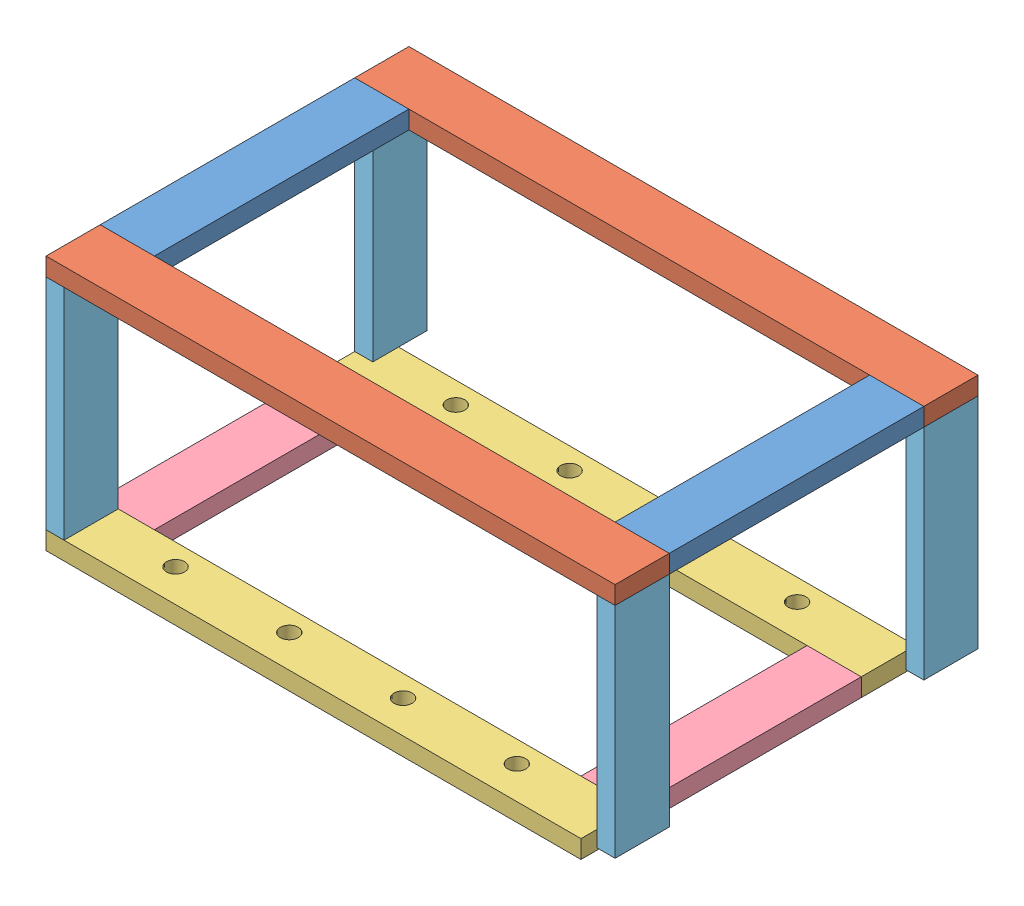
SolidWorks assembly 2.10 stand assembly, configuration Default. Lengths in mm.
Overall size (400.2 179.4 255.2).
12 component instances, 5 part files, 30 mates.
Components (placement in the parent):
- 2.10 steel stock - upper short horizontal-1: 2.10 steel stock - upper short horizontal [Default] at (-143.9565 137.1754 -48.2285) size (38.1 12.7 179)
- 2.10 steel stock - upper short horizontal-2: 2.10 steel stock - upper short horizontal [Default] at (218.1435 137.1754 -48.2285) size (38.1 12.7 179)
- 2.10 steel stock - upper long horizontal-1: 2.10 steel stock - upper long horizontal [Default] at (-143.9565 137.1754 -48.2285) size (400.2 12.7 38.1)
- 2.10 steel stock - upper long horizontal-2: 2.10 steel stock - upper long horizontal [Default] at (-143.9565 137.1754 168.8715) size (400.2 12.7 38.1)
- 2.10 steel stock - middle long horizontal-1: 2.10 steel stock - middle long horizontal [Default] at (-143.9565 -29.5246 168.8715) size (376.2 12.7 38.1)
- 2.10 steel stock - middle long horizontal-2: 2.10 steel stock - middle long horizontal [Default] at (-143.9565 -29.5246 -28.2285) size (376.2 12.7 38.1)
- 2.10 steel stock - middle short horizontal-1: 2.10 steel stock - middle short horizontal [Default] at (-143.9565 -29.5246 -28.2285) size (38.1 12.7 159)
- 2.10 steel stock - middle short horizontal-2: 2.10 steel stock - middle short horizontal [Default] at (194.1435 -29.5246 -28.2285) size (38.1 12.7 159)
- 2.10 steel stock - upper leg-1: 2.10 steel stock - upper leg [Default] at (-131.2565 -16.8246 168.8715) x (0 0 -1) z (1 0 0) size (38.1 154 12.7)
- 2.10 steel stock - upper leg-2: 2.10 steel stock - upper leg [Default] at (-131.2565 -16.8246 -48.2285) x (0 0 -1) z (1 0 0) size (38.1 154 12.7)
- 2.10 steel stock - upper leg-3: 2.10 steel stock - upper leg [Default] at (256.2435 -16.8246 -48.2285) x (0 0 -1) z (1 0 0) size (38.1 154 12.7)
- 2.10 steel stock - upper leg-4: 2.10 steel stock - upper leg [Default] at (256.2435 -16.8246 168.8715) x (0 0 -1) z (1 0 0) size (38.1 154 12.7)
Mates (geometry in assembly coordinates):
- Coincident9: coincident anti-aligned: plane of 2.10 steel stock - upper short horizontal-1 through (-143.9565 137.1754 130.7715) normal (0 0 1); plane of 2.10 steel stock - upper long horizontal-2 through (256.2435 137.1754 130.7715) normal (0 0 -1)
- Coincident10: coincident anti-aligned: plane of 2.10 steel stock - upper short horizontal-2 through (218.1435 137.1754 130.7715) normal (0 0 1); plane of 2.10 steel stock - upper long horizontal-2 through (256.2435 137.1754 130.7715) normal (0 0 -1)
- Coincident11: coincident anti-aligned: plane of 2.10 steel stock - upper short horizontal-2 through (218.1435 137.1754 -48.2285) normal (0 0 -1); plane of 2.10 steel stock - upper long horizontal-1 through (256.2435 137.1754 -48.2285) normal (0 0 1)
- Coincident13: coincident aligned: line of 2.10 steel stock - upper short horizontal-1 through (-105.8565 149.8754 130.7715) axis (-1 0 0); line of 2.10 steel stock - upper long horizontal-2 through (256.2435 149.8754 130.7715) axis (-1 0 0)
- Coincident14: coincident aligned: line of 2.10 steel stock - upper short horizontal-2 through (256.2435 149.8754 130.7715) axis (-1 0 0); line of 2.10 steel stock - upper long horizontal-2 through (256.2435 149.8754 130.7715) axis (-1 0 0)
- Coincident15: coincident aligned: line of 2.10 steel stock - upper short horizontal-2 through (256.2435 149.8754 -48.2285) axis (-1 0 0); line of 2.10 steel stock - upper long horizontal-1 through (256.2435 149.8754 -48.2285) axis (-1 0 0)
- Coincident16: coincident aligned: plane of 2.10 steel stock - upper short horizontal-2 through (256.2435 137.1754 130.7715) normal (1 0 0); plane of 2.10 steel stock - upper long horizontal-1 through (256.2435 137.1754 -48.2285) normal (1 0 0)
- Coincident17: coincident aligned: plane of 2.10 steel stock - upper short horizontal-2 through (256.2435 137.1754 130.7715) normal (1 0 0); plane of 2.10 steel stock - upper long horizontal-2 through (256.2435 137.1754 168.8715) normal (1 0 0)
- Coincident18: coincident aligned: plane of 2.10 steel stock - upper short horizontal-1 through (-143.9565 137.1754 130.7715) normal (-1 0 0); plane of 2.10 steel stock - upper long horizontal-1 through (-143.9565 137.1754 -48.2285) normal (-1 0 0)
- Coincident19: coincident anti-aligned: plane of 2.10 steel stock - middle long horizontal-1 through (232.2435 -29.5246 130.7715) normal (0 0 -1); plane of 2.10 steel stock - middle short horizontal-2 through (194.1435 -29.5246 130.7715) normal (0 0 1)
- Coincident20: coincident anti-aligned: plane of 2.10 steel stock - middle long horizontal-1 through (232.2435 -29.5246 130.7715) normal (0 0 -1); plane of 2.10 steel stock - middle short horizontal-1 through (-143.9565 -29.5246 130.7715) normal (0 0 1)
- Coincident21: coincident anti-aligned: plane of 2.10 steel stock - middle long horizontal-2 through (232.2435 -29.5246 -28.2285) normal (0 0 1); plane of 2.10 steel stock - middle short horizontal-1 through (-143.9565 -29.5246 -28.2285) normal (0 0 -1)
- Coincident22: coincident aligned: line of 2.10 steel stock - middle long horizontal-1 through (232.2435 -16.8246 130.7715) axis (-1 0 0); line of 2.10 steel stock - middle short horizontal-1 through (-105.8565 -16.8246 130.7715) axis (-1 0 0)
- Coincident23: coincident aligned: line of 2.10 steel stock - middle long horizontal-2 through (232.2435 -16.8246 -28.2285) axis (-1 0 0); line of 2.10 steel stock - middle short horizontal-1 through (-105.8565 -16.8246 -28.2285) axis (-1 0 0)
- Coincident24: coincident anti-aligned: line of 2.10 steel stock - middle long horizontal-1 through (-143.9565 -29.5246 130.7715) axis (0 1 0); line of 2.10 steel stock - middle short horizontal-1 through (-143.9565 -16.8246 130.7715) axis (0 -1 0)
- Coincident25: coincident aligned: line of 2.10 steel stock - middle long horizontal-2 through (-143.9565 -16.8246 -28.2285) axis (0 -1 0); line of 2.10 steel stock - middle short horizontal-1 through (-143.9565 -16.8246 -28.2285) axis (0 -1 0)
- Coincident26: coincident aligned: line of 2.10 steel stock - middle long horizontal-1 through (232.2435 -16.8246 130.7715) axis (-1 0 0); line of 2.10 steel stock - middle short horizontal-2 through (232.2435 -16.8246 130.7715) axis (-1 0 0)
- Coincident28: coincident aligned: line of 2.10 steel stock - middle long horizontal-1 through (232.2435 -29.5246 130.7715) axis (0 1 0); line of 2.10 steel stock - middle short horizontal-2 through (232.2435 -29.5246 130.7715) axis (0 1 0)
- Coincident29: coincident anti-aligned: plane of 2.10 steel stock - upper long horizontal-2 through (256.2435 137.1754 168.8715) normal (0 -1 0); plane of 2.10 steel stock - upper leg-4 through (256.2435 137.1754 168.8715) normal (0 1 0)
- Coincident31: coincident aligned: line of 2.10 steel stock - upper long horizontal-2 through (256.2435 137.1754 168.8715) axis (0 0 -1); line of 2.10 steel stock - upper leg-4 through (256.2435 137.1754 168.8715) axis (0 0 -1)
- Coincident32: coincident anti-aligned: line of 2.10 steel stock - upper long horizontal-2 through (256.2435 137.1754 168.8715) axis (-1 0 0); line of 2.10 steel stock - upper leg-4 through (243.5435 137.1754 168.8715) axis (1 0 0)
- Coincident33: coincident aligned: line of 2.10 steel stock - upper long horizontal-1 through (256.2435 137.1754 -48.2285) axis (0 0 -1); line of 2.10 steel stock - upper leg-3 through (256.2435 137.1754 -48.2285) axis (0 0 -1)
- Coincident34: coincident aligned: line of 2.10 steel stock - upper long horizontal-1 through (256.2435 137.1754 -86.3285) axis (-1 0 0); line of 2.10 steel stock - upper leg-3 through (256.2435 137.1754 -86.3285) axis (-1 0 0)
- Coincident35: coincident anti-aligned: line of 2.10 steel stock - upper long horizontal-2 through (-143.9565 137.1754 168.8715) axis (0 0 -1); line of 2.10 steel stock - upper leg-1 through (-143.9565 137.1754 130.7715) axis (0 0 1)
- Coincident36: coincident anti-aligned: line of 2.10 steel stock - upper long horizontal-1 through (-143.9565 137.1754 -48.2285) axis (0 0 -1); line of 2.10 steel stock - upper leg-2 through (-143.9565 137.1754 -86.3285) axis (0 0 1)
- Coincident37: coincident aligned: line of 2.10 steel stock - upper long horizontal-1 through (256.2435 137.1754 -86.3285) axis (-1 0 0); line of 2.10 steel stock - upper leg-2 through (-131.2565 137.1754 -86.3285) axis (-1 0 0)
- Coincident38: coincident anti-aligned: line of 2.10 steel stock - upper long horizontal-2 through (256.2435 137.1754 168.8715) axis (-1 0 0); line of 2.10 steel stock - upper leg-1 through (-143.9565 137.1754 168.8715) axis (1 0 0)
- Coincident39: coincident: line of 2.10 steel stock - middle long horizontal-1 through (232.2435 -16.8246 130.7715) axis (0 0 1); line of 2.10 steel stock - upper leg-4 through (256.2435 -16.8246 168.8715) axis (0 0 -1)
- Coincident40: coincident: line of 2.10 steel stock - middle long horizontal-1 through (232.2435 -16.8246 168.8715) axis (-1 0 0); plane of 2.10 steel stock - upper leg-4 through (256.2435 137.1754 168.8715) normal (0 0 1)
- Coincident41: coincident: line of 2.10 steel stock - middle long horizontal-1 through (-143.9565 -16.8246 130.7715) axis (0 0 1); line of 2.10 steel stock - upper leg-1 through (-143.9565 -16.8246 130.7715) axis (0 0 1)
